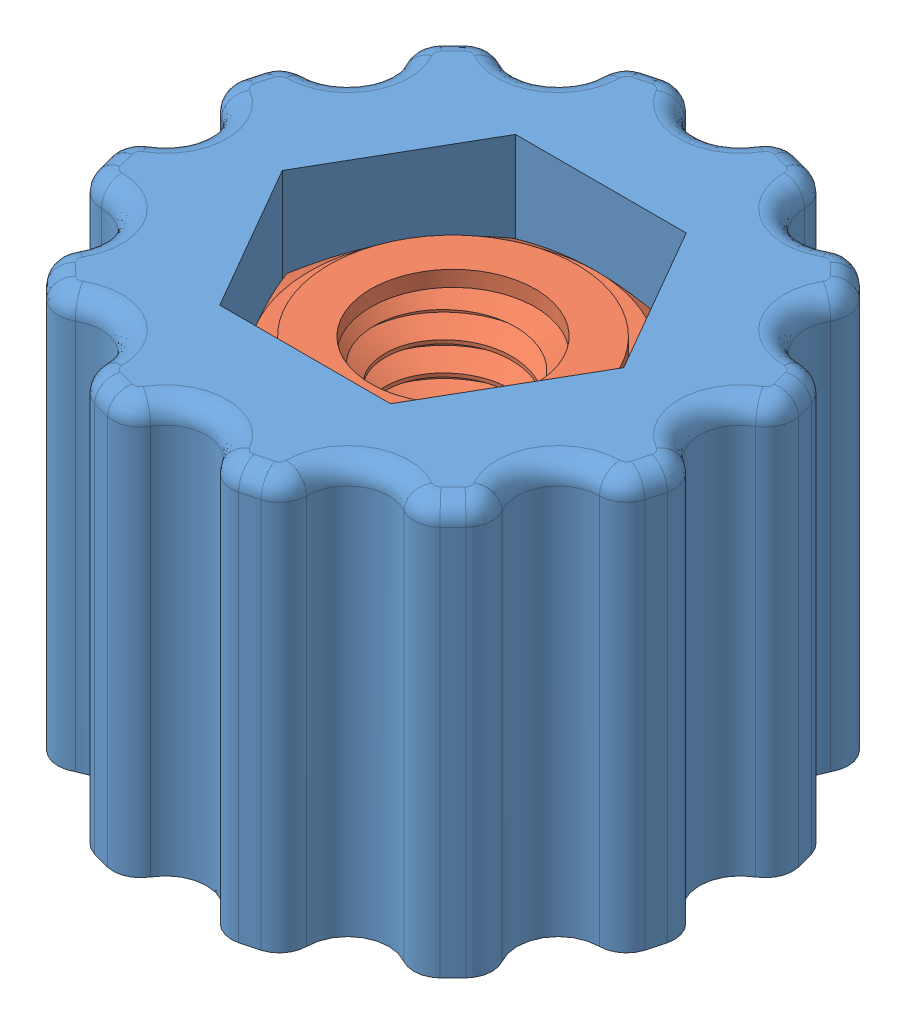
SolidWorks assembly M4_knob_assembly_P, configuration Default. Lengths in mm.
Overall size (13.67 10 13.67).
2 component instances, 2 part files, 3 mates.
Components (placement in the parent):
- Tall_Knob_P-1: Tall_Knob_P [Default] at origin size (13.67 10 13.67)
- M4 x 0.7 Hex Nut-1: M4 x 0.7 Hex Nut [90592A090] at (0 6.6 0) x (0 0 1) z (-1 0 0) size (7 3.86 8.08)
Mates (geometry in assembly coordinates):
- Concentric1: concentric: circle of Tall_Knob_P-1; circle of M4 x 0.7 Hex Nut-1
- Parallel1: parallel: plane of Tall_Knob_P-1 through (2.0785 5 -3.6) normal (0 0 1); plane of M4 x 0.7 Hex Nut-1 through (2.0207 8.2 -3.5) normal (0 0 -1)
- Coincident2: coincident anti-aligned: plane of Tall_Knob_P-1 through (0 5 0) normal (0 1 0); plane of M4 x 0.7 Hex Nut-1 through (2.0207 5 -3.5) normal (0 -1 0)
